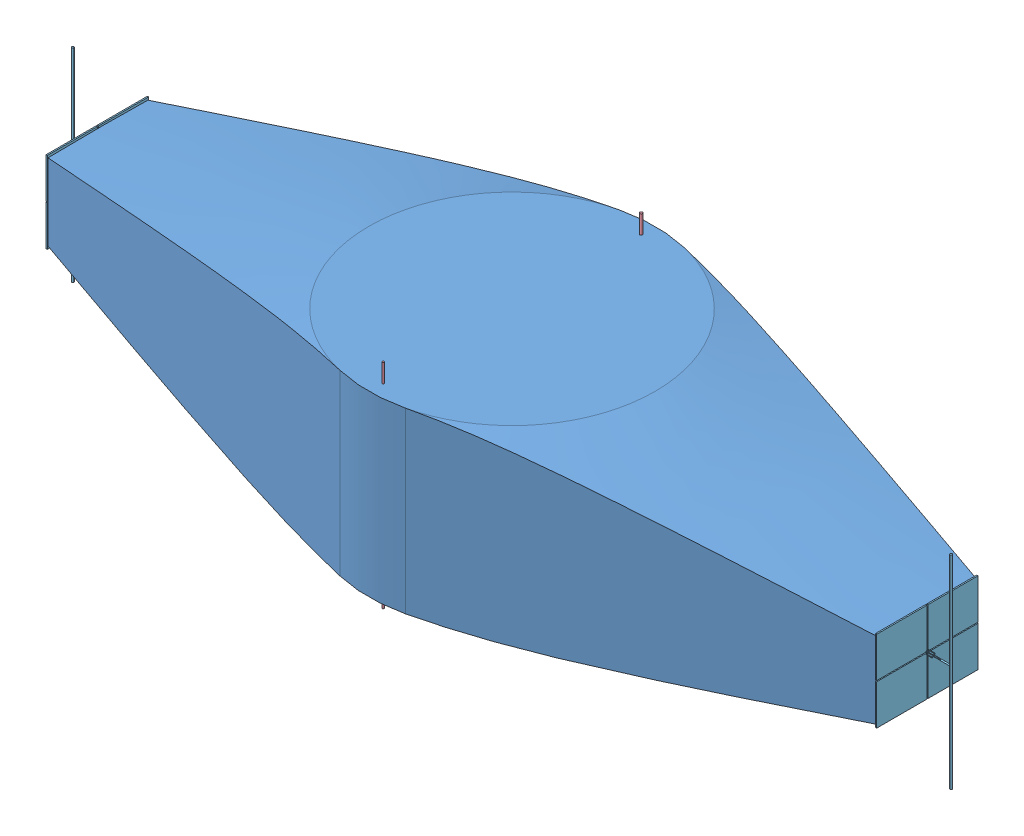
SolidWorks assembly Unit-III, configuration 默认. Lengths in mm.
Overall size (538.95 85.58 404.36).
7 component instances, 5 part files, 6 mates.
Components (placement in the parent):
- OuterShell-III-1: OuterShell-III [默认] at origin size (538.95 73.59 404.36)
- InnerUnit-1: InnerUnit [默认] at (-1.9481 30.6195 80) x (1 0 0) z (0 0 -1) size (102 85 103.7)
  - BEGeDet-2: BEGeDet [默认] at (1.9481 14.6195 80) x (1 0 0) z (0 0 -1) size (80 40 80)
  - InnerShell-3: InnerShell [默认] at (1.9481 -36.3805 80) size (102 61 102)
  - Electronics-1: Electronics [默认] at (1.9481 24.7195 80) x (-1 0 0) z (0 0 1) size (21.21 85 103.7)
- SiPMArray-1: SiPMArray [默认] at (165 35.3248 0) size (10.4 81 40.4)
- SiPMArray-2: SiPMArray [默认] at (-165 35.3248 0) x (-1 0 0) z (0 0 -1) size (10.4 81 40.4)
Mates (geometry in assembly coordinates):
- 重合1: coincident anti-aligned: plane of OuterShell-III-1 through (0 67 0) normal (0 -1 0); plane of InnerUnit-1/InnerShell-3 through (0 67 0) normal (0 1 0)
- 同心1: concentric anti-aligned: circle of OuterShell-III-1; circle of InnerUnit-1/InnerShell-3
- 重合2: coincident: point of SiPMArray-1; point of assembly
- 平行1: parallel aligned: plane of OuterShell-III-1 through (165 152 19.9043) normal (1 0 0); plane of SiPMArray-1 through (165.5 35.3248 0) normal (1 0 0)
- 平行2: parallel anti-aligned: line of OuterShell-III-1 through (165 46.5784 -15.7961) axis (0 -1 0); line of SiPMArray-1 through (165.5 35.5248 -20.2) axis (0 1 0)
- 重合5: coincident anti-aligned: plane of OuterShell-III-1 through (-165 152 -19.9043) normal (-1 0 0); plane of SiPMArray-2 through (-165 35.3248 0) normal (1 0 0)
